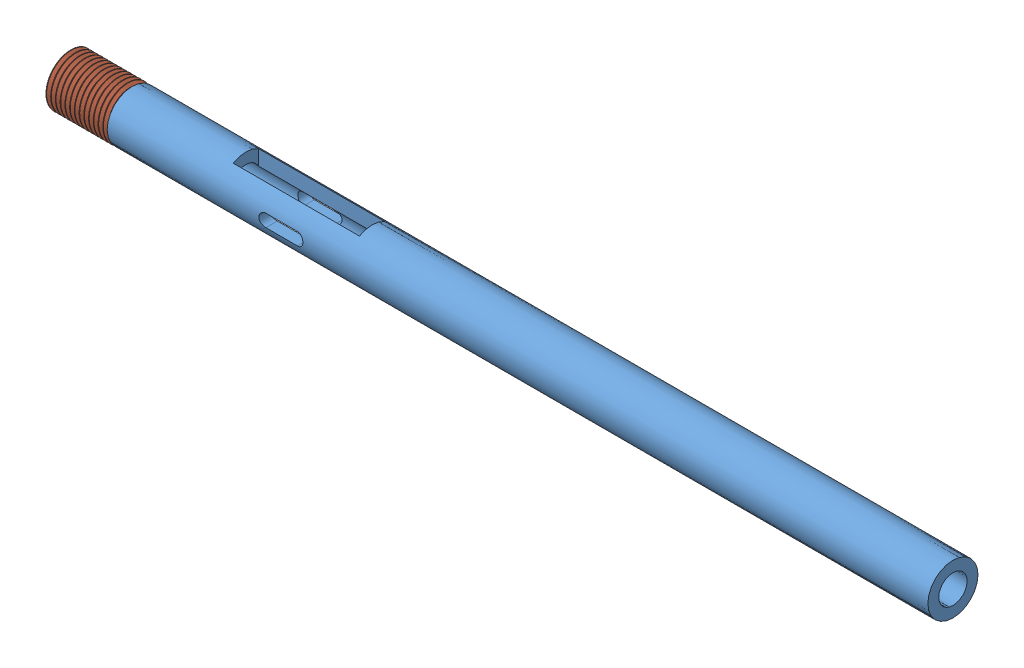
SolidWorks assembly slider handle assembly v-4 06-Nov-2017, configuration Default. Lengths in mm.
Overall size (140.35 13 13).
2 component instances, 2 part files, 2 mates.
Components (placement in the parent):
- wheel_handle_body_slider v-4 06-Nov-2017-1: wheel_handle_body_slider v-4 06-Nov-2017 [Default] at (-10.0168 48.9172 77.5775) size (130 7.94 7.94)
- M8X0.75-1: M8X0.75 [91290A414] at (-10.0168 48.9172 77.5775) x (0 0 -1) z (1 0 0) size (13 13 10.51)
Mates (geometry in assembly coordinates):
- Coincident1: coincident anti-aligned: plane of wheel_handle_body_slider v-4 06-Nov-2017-1 through (-10.0168 48.9172 77.5775) normal (-1 0 0); plane of M8X0.75-1 through (-10.0168 48.9172 77.5775) normal (1 0 0)
- Concentric1: concentric anti-aligned: circle of wheel_handle_body_slider v-4 06-Nov-2017-1; circle of M8X0.75-1
